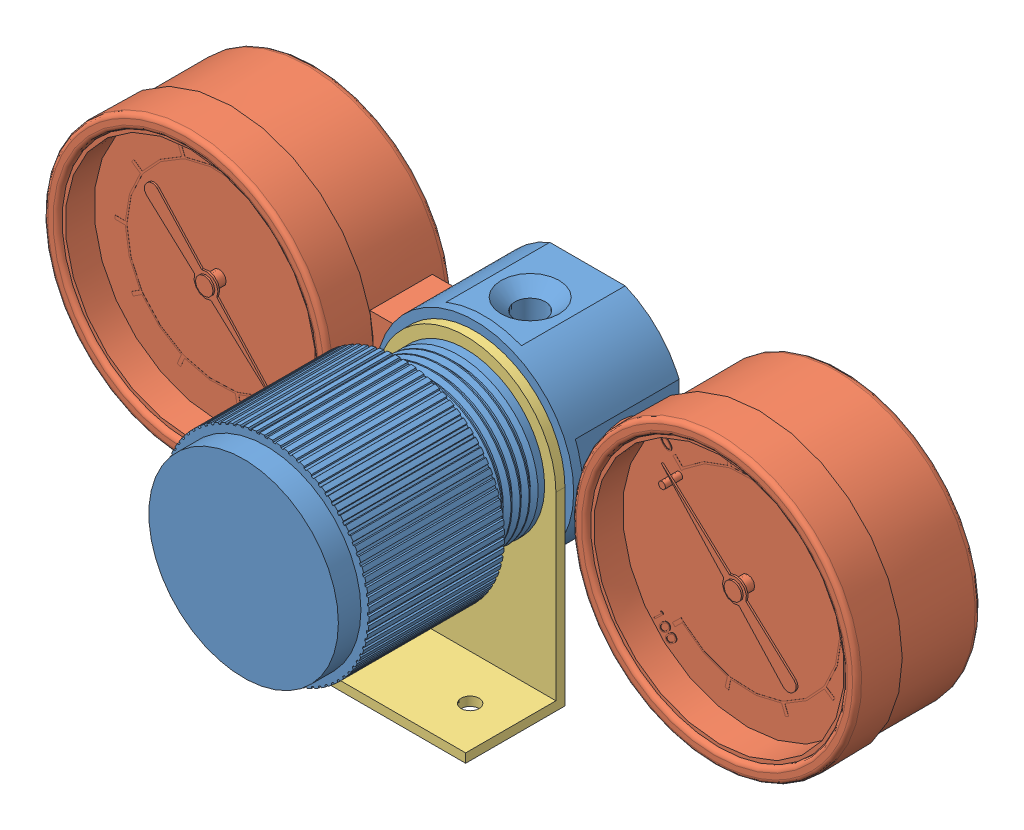
SolidWorks assembly Assem2, configuration Default. Lengths in mm.
Overall size (180.35 73.62 76.2).
4 component instances, 3 part files, 9 mates.
Components (placement in the parent):
- SE_01_2_2001-1: SE_01_2_2001 [Default] at origin size (45.69 45.69 76.2)
- SE_01_2_2002-1: SE_01_2_2002 [Default] at (-58.5509 0 30.4289) x (0 1 0) z (0 0 1) size (63.25 91.66 28.83)
- SE_01_2_2002-2: SE_01_2_2002 [Default] at (58.5509 0 30.4289) x (0 -1 0) z (0 0 1) size (63.25 91.66 28.83)
- SE_01_2_2003-1: SE_01_2_2003 [Default] at (20 -42 25) x (0 0 1) z (-1 0 0) size (22 62 40)
Mates (geometry in assembly coordinates):
- Concentric1: concentric aligned: cylinder of SE_01_2_2001-1 through (-20.3 0 12.7) axis (-1 0 0) radius 3.3782; cylinder of SE_01_2_2002-1 through (-8.5129 0 12.7) axis (-1 0 0) radius 6.9215
- Coincident1: coincident: cone of SE_01_2_2001-1 through (-20.3 0 12.7) axis (1 0 0); circle of SE_01_2_2002-1
- Concentric2: concentric aligned: cylinder of SE_01_2_2001-1 through (20.3 0 12.7) axis (1 0 0) radius 3.3782; cylinder of SE_01_2_2002-2 through (8.5129 0 12.7) axis (1 0 0) radius 6.9215
- Coincident2: coincident: cone of SE_01_2_2001-1 through (20.3 0 12.7) axis (-1 0 0); circle of SE_01_2_2002-2
- Parallel1: parallel aligned: plane of SE_01_2_2001-1 through (0 0 0) normal (0 0 -1); plane of SE_01_2_2002-2 through (58.5509 0 1.8539) normal (0 0 -1)
- Parallel2: parallel aligned: plane of SE_01_2_2001-1 through (0 0 0) normal (0 0 -1); plane of SE_01_2_2002-1 through (-58.5509 0 1.8539) normal (0 0 -1)
- Coincident4: coincident: plane of SE_01_2_2001-1 through (0 0 25) normal (0 0 1); plane of SE_01_2_2003-1 through (-20 -42 25) normal (0 0 -1)
- Concentric3: concentric: cylinder of SE_01_2_2001-1 through (0 0 76.2) axis (0 0 -1) radius 17.5; cylinder of SE_01_2_2003-1 through (0 0 24.999) axis (0 0 1) radius 20
- Parallel3: parallel aligned: plane of SE_01_2_2001-1 through (0 20.3 23) normal (0 1 0); plane of SE_01_2_2003-1 through (-20 -40 27) normal (0 1 0)
